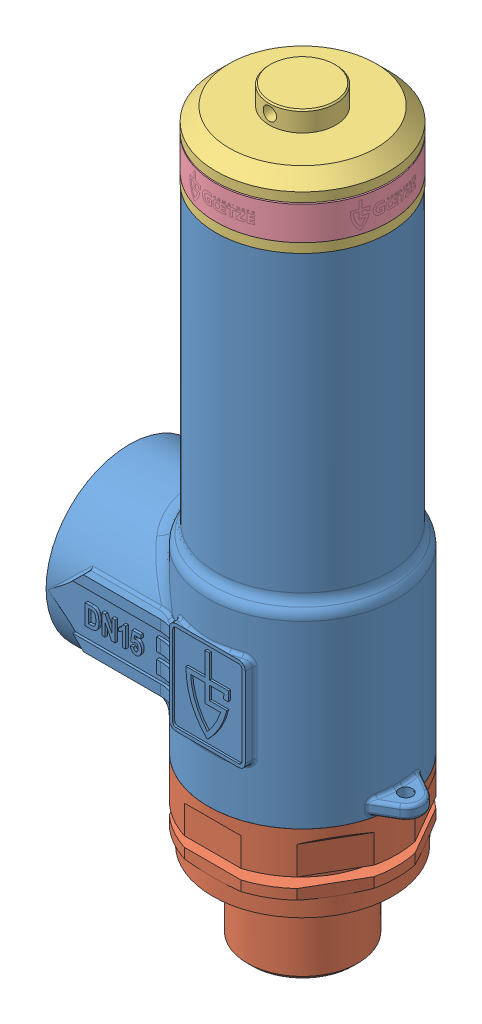
SolidWorks assembly 2480TGFO8_MF_1015_PTFE, configuration Standard. Lengths in mm.
Overall size (44 117.5 28.6).
4 component instances, 4 part files, 11 mates.
Components (placement in the parent):
- 24800150008-1: 24800150008 [Standard] at (0 24 0) size (44 74.09 28.6)
- 02-2400-15-3-8 Sitz-1: 02-2400-15-3-8 Sitz [Standard] at origin size (28.3 33.3 28.3)
- 24800150011-1: 24800150011 [Standard] at (0 91 0) x (0 0 -1) z (1 0 0) size (26 26.5 26)
- 24000150048-1: 24000150048 [Standard] at (0 99.4 0) size (26 5 26)
Mates (geometry in assembly coordinates):
- Deckungsgleich1: coordinate: point of 02-2400-15-3-8 Sitz-1; point of assembly
- Deckungsgleich2: coincident aligned: plane of 24800150008-1 through (0 24 0) normal (0 0 1); plane of assembly through (0 0 0) normal (0 0 1)
- Deckungsgleich3: coincident anti-aligned: plane of 02-2400-15-3-8 Sitz-1 through (0 24 14.15) normal (0 1 0); plane of 24800150008-1 through (0 24 0) normal (0 -1 0)
- Deckungsgleich4: coincident aligned: line of 24800150008-1 through (110 0 78.2399) axis (0 0 -1); line of assembly
- Deckungsgleich5: coincident aligned: plane of 02-2400-15-3-8 Sitz-1 through (0 0 0) normal (0 0 1); plane of assembly through (0 0 0) normal (0 0 1)
- Deckungsgleich68: coincident anti-aligned: plane of 24800150011-1 through (0 91 0) normal (0 0 -1); plane of assembly through (0 0 0) normal (0 0 1)
- Deckungsgleich69: coincident anti-aligned: plane of 24800150008-1 through (0 98 0) normal (0 1 0); plane of 24800150011-1 through (0 98 13) normal (0 -1 0)
- Deckungsgleich70: coincident aligned: line of 24800150011-1 through (92.5993 0 179.3903) axis (0 0 -1); line of assembly
- Deckungsgleich71: coincident anti-aligned: plane of 24800150011-1 through (0 99.4 15.653) normal (0 1 0); plane of 24000150048-1 through (0 99.4 0) normal (0 -1 0)
- Deckungsgleich72: coincident aligned: plane of 24000150048-1 through (0 99.4 0) normal (0 0 1); plane of assembly through (0 0 0) normal (0 0 1)
- Deckungsgleich73: coincident aligned: line of 24000150048-1 through (5.5 0 104.65) axis (0 0 -1); line of assembly
